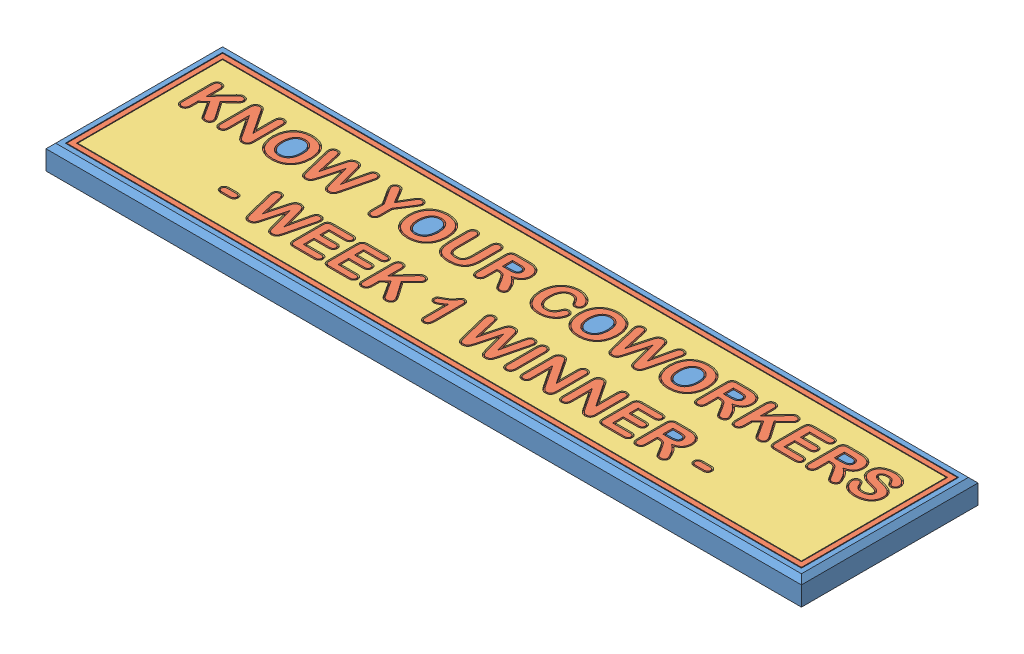
SolidWorks assembly three_part_test_big, configuration Default. Lengths in mm.
Overall size (156.6 5 36.6).
3 component instances, 3 part files, 6 mates.
Components (placement in the parent):
- three_part_test_big_bottom-1: three_part_test_big_bottom [Default] at origin size (156.6 5 36.6)
- three_part_test_big_middle-1: three_part_test_big_middle [Default] at (0 4 0) size (152.3 1 32.3)
- three_part_test_big_top-1: three_part_test_big_top [Default] at (0 4.5 0) size (150 0.5 30)
Mates (geometry in assembly coordinates):
- Coincident1: coincident aligned: plane of three_part_test_big_middle-1 through (0 4 0) normal (0 0 1); plane of assembly through (0 0 0) normal (0 0 1)
- Coincident2: coincident aligned: plane of three_part_test_big_top-1 through (0 4.5 0) normal (0 0 1); plane of assembly through (0 0 0) normal (0 0 1)
- Coincident3: coincident aligned: plane of three_part_test_big_middle-1 through (0 4 0) normal (1 0 0); plane of assembly through (0 0 0) normal (1 0 0)
- Coincident4: coincident aligned: plane of three_part_test_big_top-1 through (0 4.5 0) normal (1 0 0); plane of assembly through (0 0 0) normal (1 0 0)
- Coincident5: coincident aligned: plane of three_part_test_big_bottom-1 through (0 5 0) normal (0 1 0); plane of three_part_test_big_middle-1 through (0 5 0) normal (0 1 0)
- Coincident6: coincident aligned: plane of three_part_test_big_bottom-1 through (0 5 0) normal (0 1 0); plane of three_part_test_big_top-1 through (0 5 0) normal (0 1 0)
